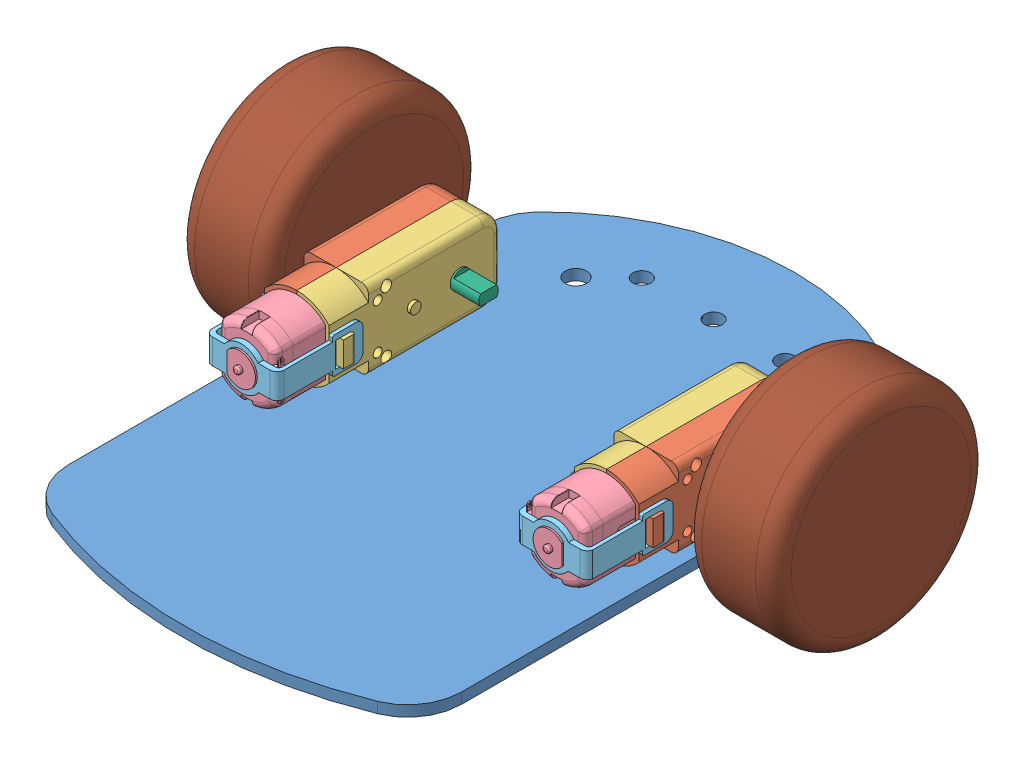
SolidWorks assembly Assem coba, configuration Default. Lengths in mm.
Overall size (166.41 84.85 170.53).
24 component instances, 12 part files, 10 mates.
Components (placement in the parent):
- Base-1: Base [Default] at origin size (109.69 3 170.53)
- Motor DC.stp-1: Motor DC.stp [Default] at (75.9512 41.8293 18.6) x (0 0 1) z (-1 0 0) size (70 22 34.5)
  - gearbox.stp-1: gearbox.stp [Default] at (-35.6927 -38.8293 23.6559) size (53 22 15)
  - gearbox_1.stp-1: gearbox_1.stp [Default] at (-35.6927 -16.8293 41.6559) x (1 0 0) z (0 0 -1) size (53 22 11)
  - motor_dc.stp-1: motor_dc.stp [Default] at (1.3073 -27.8293 32.6559) x (0 -1 0) z (1 0 0) size (20 17.05 35.5)
  - Part1.stp-1: Part1.stp [Default] at (28.3073 -27.8293 32.6242) x (0 -1 0) z (1 0 0) size (11.87 20.06 24)
  - gear1.stp-1: gear1.stp [Default] at (-24.1927 -27.8293 40.1559) x (1 0 0) z (0 0 -1) size (16.82 16.85 34.5)
  - gear2.stp-1: gear2.stp [Default] at (-24.1927 -27.8293 30.6559) size (19.8 19.83 7.5)
  - Part2.stp-1: Part2.stp [Default] at (-10.9927 -27.8293 26.6559) size (5 5 17)
  - gear3.stp-1: gear3.stp [Default] at (-10.9927 -27.8293 26.6559) size (15.01 15.03 6)
  - gear4.stp-1: gear4.stp [Default] at (-10.9927 -27.8293 36.9059) size (17.81 17.81 3.75)
- Motor DC.stp-2: Motor DC.stp [Default] at (-75.7704 -13.8293 18.6) x (0 0 1) z (1 0 0) size (70 22 34.5)
  - gearbox.stp-1: gearbox.stp [Default] at (-35.6927 -38.8293 23.6559) size (53 22 15)
  - gearbox_1.stp-1: gearbox_1.stp [Default] at (-35.6927 -16.8293 41.6559) x (1 0 0) z (0 0 -1) size (53 22 11)
  - motor_dc.stp-1: motor_dc.stp [Default] at (1.3073 -27.8293 32.6559) x (0 -1 0) z (1 0 0) size (20 17.05 35.5)
  - Part1.stp-1: Part1.stp [Default] at (28.3073 -27.8293 32.6242) x (0 -1 0) z (1 0 0) size (11.87 20.06 24)
  - gear1.stp-1: gear1.stp [Default] at (-24.1927 -27.8293 40.1559) x (1 0 0) z (0 0 -1) size (16.82 16.85 34.5)
  - gear2.stp-1: gear2.stp [Default] at (-24.1927 -27.8293 30.6559) size (19.8 19.83 7.5)
  - Part2.stp-1: Part2.stp [Default] at (-10.9927 -27.8293 26.6559) size (5 5 17)
  - gear3.stp-1: gear3.stp [Default] at (-10.9927 -27.8293 26.6559) size (15.01 15.03 6)
  - gear4.stp-1: gear4.stp [Default] at (-10.9927 -27.8293 36.9059) size (17.81 17.81 3.75)
- ceritanya roda pinggir-1: ceritanya roda pinggir [Default] at (-58.1145 14 -5.5927) x (0 -0.15339 0.988166) z (-1 0 0) size (60 60 25)
- ceritanya roda pinggir-2: ceritanya roda pinggir [Default] at (58.2952 14 -5.5927) x (0 -0.70642 -0.707793) z (1 0 0) size (60 60 25)
- ceritanya roda tengah-1: ceritanya roda tengah [Default] at (0 -12 72.4993) size (20 20.75 27.76)
Mates (geometry in assembly coordinates):
- Parallel1: parallel anti-aligned: plane of Base-1 through (37.3603 3 -32.0701) normal (0 1 0); plane of Motor DC.stp-1/gearbox_1.stp-1 through (34.2952 3 19.9073) normal (0 -1 0)
- Coincident1: coincident anti-aligned: plane of Base-1 through (37.3603 3 -32.0701) normal (0 1 0); plane of Motor DC.stp-1/gearbox.stp-1 through (52.2952 3 -17.0927) normal (0 -1 0)
- Coincident6: coincident anti-aligned: plane of Base-1 through (37.3603 3 -32.0701) normal (0 1 0); plane of Motor DC.stp-2/gearbox_1.stp-1 through (-34.1145 3 -17.0927) normal (0 -1 0)
- Concentric1: concentric anti-aligned: cylinder of Motor DC.stp-1/gear1.stp-1 through (35.7952 14 -5.5927) axis (1 0 0) radius 2.7; circle of ceritanya roda pinggir-2
- Distance1: distance = 5 mm anti-aligned: plane of Motor DC.stp-1/gear1.stp-1 through (53.2952 15.8695 -5.5927) normal (1 0 0); plane of ceritanya roda pinggir-2 through (58.2952 14 -5.5927) normal (-1 0 0)
- Coincident11: coincident aligned: plane of Motor DC.stp-1/gearbox_1.stp-1 through (34.2952 3 -17.0927) normal (0 0 -1); plane of Motor DC.stp-2/gearbox_1.stp-1 through (-34.1145 25 -17.0927) normal (0 0 -1)
- Concentric2: concentric anti-aligned: cylinder of Motor DC.stp-2/gear1.stp-1 through (-35.6145 14 -5.5927) axis (-1 0 0) radius 2.7; circle of ceritanya roda pinggir-1
- Distance2: distance = 5 mm anti-aligned: plane of Motor DC.stp-2/gear1.stp-1 through (-53.1145 15.8695 -5.5927) normal (-1 0 0); plane of ceritanya roda pinggir-1 through (-58.1145 14 -5.5927) normal (1 0 0)
- Coincident12: coincident anti-aligned: plane of Base-1 through (37.3603 0 -32.0701) normal (0 -1 0); plane of ceritanya roda tengah-1 through (0 0 72.4993) normal (0 1 0)
- Width1: width aligned: plane of ceritanya roda tengah-1 through (-7.5 0 86.3772) normal (-1 0 0); plane of Base-1 through (7.5 0 86.3772) normal (1 0 0); plane of ceritanya roda tengah-1 through (-54.8439 3 82.9506) normal (-1 0 0); plane of Base-1 through (54.8439 3 82.9506) normal (1 0 0)
